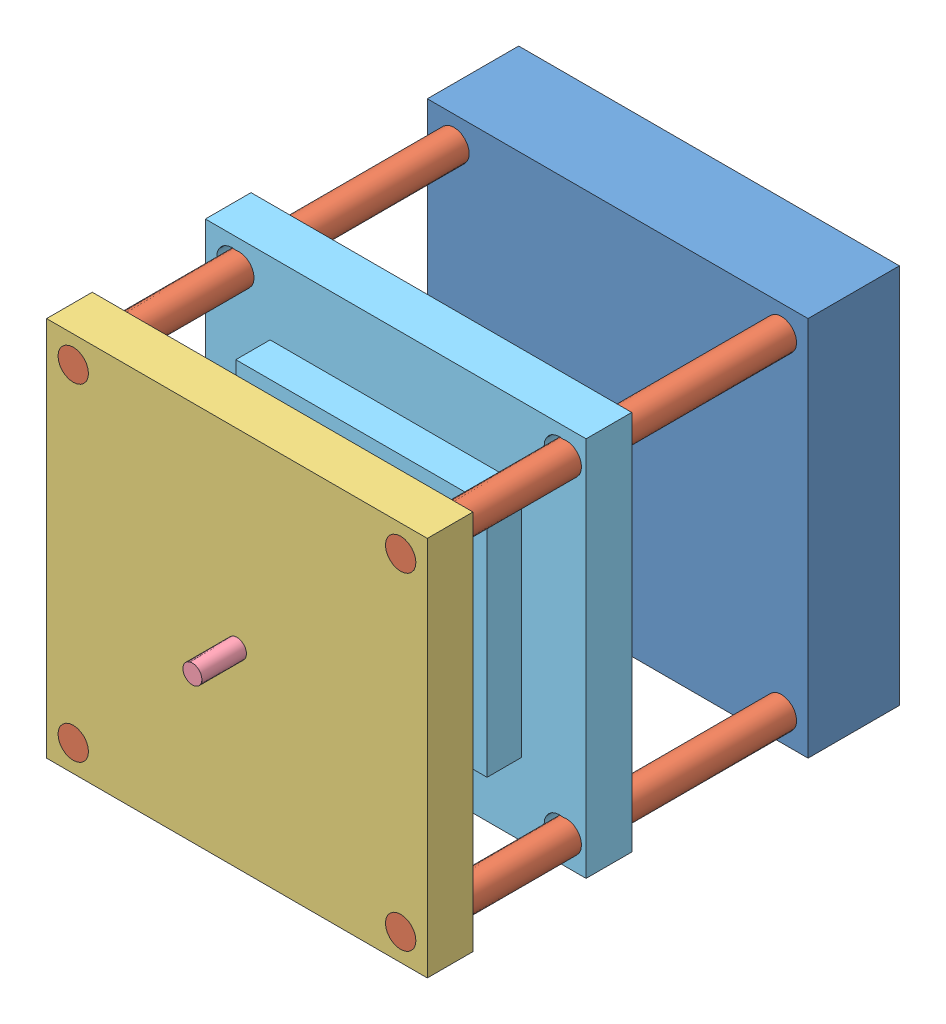
SolidWorks assembly Ensamblaje_Base, configuration Predeterminado. Lengths in mm.
Overall size (101.8 100 135.7).
8 component instances, 5 part files, 20 mates.
Components (placement in the parent):
- Pieza8-1: Pieza8 [Predeterminado] x (-1 0 0) z (0 1 0) size (100 24 100)
- Pieza6-1: Pieza6 [Predeterminado] at (-43 -43 0) x (1 0 0) z (0 -1 0) size (8 124 8)
- Pieza6-2: Pieza6 [Predeterminado] at (43 43 0) x (1 0 0) z (0 -1 0) size (8 124 8)
- Pieza6-3: Pieza6 [Predeterminado] at (43 -43 0) x (1 0 0) z (0 -1 0) size (8 124 8)
- Pieza6-4: Pieza6 [Predeterminado] at (-43 43 0) x (1 0 0) z (0 -1 0) size (8 124 8)
- Pieza4-1: Pieza4 [Predeterminado] at (0 0 112) x (1 0 0) z (0 -1 0) size (100 12 100)
- Motor Paso a Paso-1: Motor Paso a Paso [Predeterminado] at (0 0 80.5) x (0 -1 0) z (-1 0 0) size (42 55.2 46)
- Pieza7-1: Pieza7 [Predeterminado] at (-1.8 0 80.5) x (0 -1 0) z (-1 0 0) size (100 21 100)
Mates (geometry in assembly coordinates):
- Coincidente7: coincident aligned: plane of Pieza8-1 through (0 0 0) normal (0 0 1)
- Coincidente8: coincident aligned: plane of Pieza8-1 through (0 0 0) normal (0 1 0)
- Coincidente9: coincident anti-aligned: plane of Pieza8-1 through (0 0 0) normal (-1 0 0)
- Concéntrica1: concentric anti-aligned: cylinder of Pieza8-1 through (-43 43 -11.3137) axis (0 0 1) radius 4; cylinder of Pieza6-4 through (-43 43 124) axis (0 0 -1) radius 4
- Coincidente10: coincident aligned: plane of Pieza8-1 through (0 0 0) normal (0 0 -1); plane of Pieza6-4 through (-43 43 0) normal (0 0 -1)
- Concéntrica2: concentric anti-aligned: cylinder of Pieza8-1 through (-43 -43 -11.3137) axis (0 0 1) radius 4; cylinder of Pieza6-1 through (-43 -43 124) axis (0 0 -1) radius 4
- Coincidente11: coincident aligned: plane of Pieza8-1 through (0 0 0) normal (0 0 -1); plane of Pieza6-1 through (-43 -43 0) normal (0 0 -1)
- Concéntrica3: concentric anti-aligned: cylinder of Pieza8-1 through (43 43 -11.3137) axis (0 0 1) radius 4; cylinder of Pieza6-2 through (43 43 124) axis (0 0 -1) radius 4
- Coincidente12: coincident aligned: plane of Pieza8-1 through (0 0 0) normal (0 0 -1); plane of Pieza6-2 through (43 43 0) normal (0 0 -1)
- Concéntrica4: concentric anti-aligned: cylinder of Pieza8-1 through (43 -43 -11.3137) axis (0 0 1) radius 4; cylinder of Pieza6-3 through (43 -43 124) axis (0 0 -1) radius 4
- Coincidente13: coincident aligned: plane of Pieza8-1 through (0 0 0) normal (0 0 -1); plane of Pieza6-3 through (43 -43 0) normal (0 0 -1)
- Concéntrica5: concentric anti-aligned: cylinder of Pieza6-3 through (43 -43 124) axis (0 0 -1) radius 4; cylinder of Pieza4-1 through (43 -43 100.6863) axis (0 0 1) radius 4
- Concéntrica6: concentric anti-aligned: cylinder of Pieza6-2 through (43 43 124) axis (0 0 -1) radius 4; cylinder of Pieza4-1 through (43 43 100.6863) axis (0 0 1) radius 4
- Coincidente14: coincident aligned: plane of Pieza6-4 through (-43 43 124) normal (0 0 1); plane of Pieza4-1 through (0 0 124) normal (0 0 1)
- Coincidente15: coincident anti-aligned: plane of Pieza4-1 through (0 0 113.7) normal (0 0 -1); plane of Motor Paso a Paso-1 through (0 0 113.7) normal (0 0 1)
- Coincidente16: coincident anti-aligned: plane of Pieza4-1 through (-21.2 21 113.7) normal (1 0 0); plane of Motor Paso a Paso-1 through (-21.2 16 113.7) normal (-1 0 0)
- Concéntrica9: concentric aligned: cylinder of Pieza4-1 through (0 0 115.7) axis (0 0 -1) radius 11; cylinder of Motor Paso a Paso-1 through (0 0 115.7) axis (0 0 -1) radius 11
- Coincidente18: coincident anti-aligned: plane of Motor Paso a Paso-1 through (0 0 80.5) normal (0 0 -1); plane of Pieza7-1 through (-1.8 0 80.5) normal (0 0 1)
- Coincidente19: coincident anti-aligned: plane of Motor Paso a Paso-1 through (-21.2 -21 90) normal (0 -1 0); plane of Pieza7-1 through (-24.8 -21 89.5) normal (0 1 0)
- Coincidente20: coincident anti-aligned: plane of Motor Paso a Paso-1 through (21.2 21 90) normal (1 0 0); plane of Pieza7-1 through (21.2 21 89.5) normal (-1 0 0)
